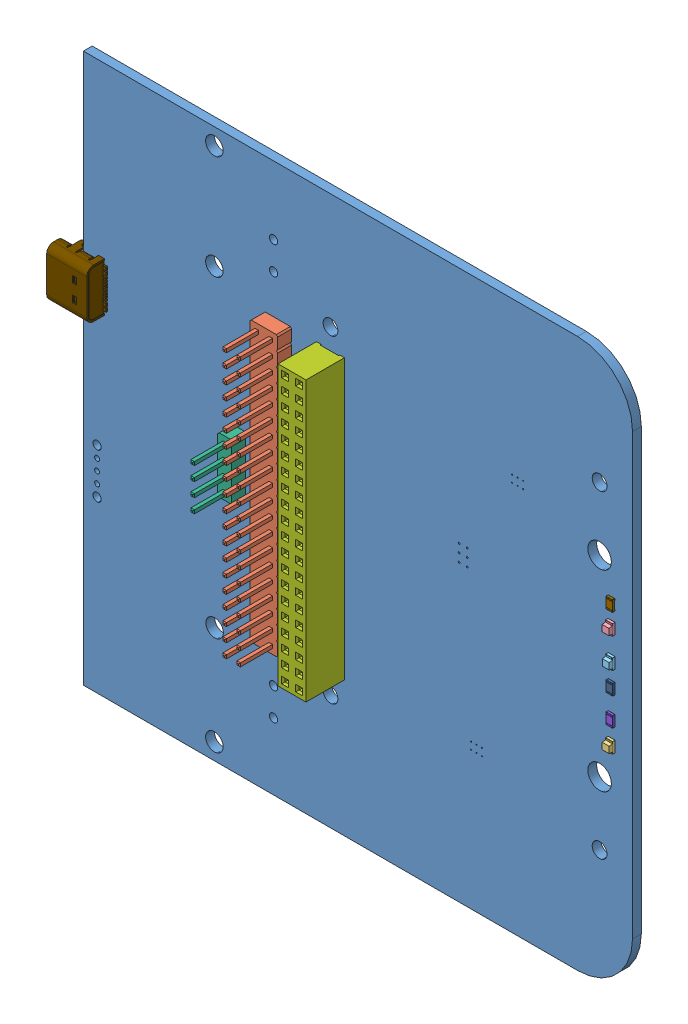
SolidWorks assembly car pcb, configuration 默认. Lengths in mm.
Overall size (103.47 100 12.36).
60 component instances, 54 part files, 4 mates.
Components (placement in the parent):
- car pcb(2)-1: car pcb(2) [默认] at origin size (100 100 12.36)
  - Board_Geoms-1: Board_Geoms [默认] at origin size (100 100 1.6)
    - Pcb-1: Pcb [默认] at (-97.365 149.231 0) size (100 100 1.6)
      - Open CASCADE STEP translator 7.3 1.1.1.1^Pcb-1: Open CASCADE STEP translator 7.3 1.1.1.1^Pcb [默认] at origin size (100 100 1.6) (virtual)
  - Step_Models-1: Step_Models [默认] at origin size (69.83 72.3 12.36)
    - Top-1: Top [默认] at origin size (69.83 50.8 11.64)
      - J6_PinHeader_2x20_P254mm_Vertical_5E973953-1: J6_PinHeader_2x20_P254mm_Vertical_5E973953 [默认] at (34.12 74.135 0) size (5.08 50.8 11.54)
      - D1_LED_0805_2012Metric_5E97381B-1: D1_LED_0805_2012Metric_5E97381B [默认] at (96.209 38.751 0) x (0 1 0) z (0 0 1) size (2 1.25 1.1)
      - D3_LED_0805_2012Metric_5E973846-1: D3_LED_0805_2012Metric_5E973846 [默认] at (96.182 57.3275 0) x (0 1 0) z (0 0 1) size (2 1.25 1.1)
      - D5_LED_0805_2012Metric_5E973871-1: D5_LED_0805_2012Metric_5E973871 [默认] at (96.218 51.946 0) x (0 -1 0) z (0 0 1) size (2 1.25 1.1)
      - J2_PinHeader_1x04_P254mm_Vertical_5E9738C1-1: J2_PinHeader_1x04_P254mm_Vertical_5E9738C1 [默认] at (28.278 53.434 0) size (2.54 10.16 11.54)
      - J5_PinSocket_2x20_P254mm_Vertical_5E975A58-1: J5_PinSocket_2x20_P254mm_Vertical_5E975A58 [默认] at (46.26 74.13 0) size (5.08 50.8 10.1)
      - R4_R_0805_2012Metric_5E99E94D-1: R4_R_0805_2012Metric_5E99E94D [默认] at (96.209 42.815 0) x (0 -1 0) z (0 0 1) size (2 1.2 0.45)
      - R18_R_0805_2012Metric_5E9C048F-1: R18_R_0805_2012Metric_5E9C048F [默认] at (96.182 61.059 0) x (0 -1 0) z (0 0 1) size (2 1.2 0.45)
      - R21_R_0805_2012Metric_5E973B6B-1: R21_R_0805_2012Metric_5E973B6B [默认] at (96.218 47.882 0) x (0 -1 0) z (0 0 1) size (2 1.2 0.45)
    - Bot-1: Bot [默认] at origin size (34.4 72.3 2.22)
      - C5_C_0805_2012Metric_5E97372B-1: C5_C_0805_2012Metric_5E97372B [默认] at (76.411 51.91 -1.6) x (1 0 0) z (0 0 -1) size (2 1.25 1.25)
      - R15_R_0805_2012Metric_5E973B05-1: R15_R_0805_2012Metric_5E973B05 [默认] at (81.491 78.453 -1.6) x (0 1 0) z (0 0 -1) size (2 1.2 0.45)
      - C1_C_1206_3216Metric_5E9736E7-1: C1_C_1206_3216Metric_5E9736E7 [默认] at (50.95 81.1 -1.6) x (0 1 0) z (0 0 -1) size (3.2 1.6 1.6)
      - C2_C_0805_2012Metric_5E9736F8-1: C2_C_0805_2012Metric_5E9736F8 [默认] at (51.5 75.6 -1.6) x (-1 0 0) z (0 0 -1) size (2 1.25 1.25)
      - C3_C_0805_2012Metric_5E973709-1: C3_C_0805_2012Metric_5E973709 [默认] at (76.411 59.403 -1.6) x (-1 0 0) z (0 0 -1) size (2 1.25 1.25)
      - C4_C_1206_3216Metric_5E97BBAC-1: C4_C_1206_3216Metric_5E97BBAC [默认] at (77.046 56.609 -1.6) x (-1 0 0) z (0 0 -1) size (3.2 1.6 1.6)
      - C6_C_0805_2012Metric_5E97B6B1-1: C6_C_0805_2012Metric_5E97B6B1 [默认] at (61.552 53.434 -1.6) x (-1 0 0) z (0 0 -1) size (2 1.25 1.25)
      - C7_C_0805_2012Metric_5E97374D-1: C7_C_0805_2012Metric_5E97374D [默认] at (61.552 56.736 -1.6) x (1 0 0) z (0 0 -1) size (2 1.25 1.25)
      - C8_C_1206_3216Metric_5E97375E-1: C8_C_1206_3216Metric_5E97375E [默认] at (77.046 65.245 -1.6) x (1 0 0) z (0 0 -1) size (3.2 1.6 1.6)
      - C9_C_0805_2012Metric_5E97376F-1: C9_C_0805_2012Metric_5E97376F [默认] at (74.506 69.563 -1.6) x (0 -1 0) z (0 0 -1) size (2 1.25 1.25)
      - C10_C_0805_2012Metric_5E973780-1: C10_C_0805_2012Metric_5E973780 [默认] at (79.078 78.453 -1.6) x (0 1 0) z (0 0 -1) size (2 1.25 1.25)
      - C11_C_1206_3216Metric_5E973791-1: C11_C_1206_3216Metric_5E973791 [默认] at (63.076 69.182 -1.6) x (1 0 0) z (0 0 -1) size (3.2 1.6 1.6)
      - C12_C_1206_3216Metric_5E977737-1: C12_C_1206_3216Metric_5E977737 [默认] at (62.441 23.081 -1.6) x (0 1 0) z (0 0 -1) size (3.2 1.6 1.6)
      - C13_C_1206_3216Metric_5E978263-1: C13_C_1206_3216Metric_5E978263 [默认] at (59.52 23.081 -1.6) x (0 1 0) z (0 0 -1) size (3.2 1.6 1.6)
      - C14_C_1206_3216Metric_5E9737C4-1: C14_C_1206_3216Metric_5E9737C4 [默认] at (79.459 27.018 -1.6) x (-1 0 0) z (0 0 -1) size (3.2 1.6 1.6)
      - C15_C_1206_3216Metric_5E9737D5-1: C15_C_1206_3216Metric_5E9737D5 [默认] at (79.459 23.97 -1.6) x (-1 0 0) z (0 0 -1) size (3.2 1.6 1.6)
      - C16_C_0805_2012Metric_5E9737E6-1: C16_C_0805_2012Metric_5E9737E6 [默认] at (65.997 26.002 -1.6) x (-1 0 0) z (0 0 -1) size (2 1.25 1.25)
      - C17_C_0805_2012Metric_5E9737F7-1: C17_C_0805_2012Metric_5E9737F7 [默认] at (80.059 29.939 -1.6) x (-1 0 0) z (0 0 -1) size (2 1.25 1.25)
      - C18_C_1206_3216Metric_5E973808-1: C18_C_1206_3216Metric_5E973808 [默认] at (73.109 18.036 -1.6) x (0 -1 0) z (0 0 -1) size (3.2 1.6 1.6)
      - D2_D_SMA_5E9BCED4-1: D2_D_SMA_5E9BCED4 [默认] at (70.823 71.468 -1.6) x (0 -1 0) z (0 0 -1) size (5 2.7 2.22)
      - D4_D_SMA_5E9777E8-1: D4_D_SMA_5E9777E8 [默认] at (78.316 33.495 -1.6) x (-1 0 0) z (0 0 -1) size (5 2.7 2.22)
      - Q1_SOT_23_5E99EF72-1: Q1_SOT_23_5E99EF72 [默认] at (59.266 15.207 -1.6) x (-1 0 0) z (0 0 -1) size (2.5 3 1.2)
      - R1_R_0805_2012Metric_5E973A17-1: R1_R_0805_2012Metric_5E973A17 [默认] at (62.695 11.397 -1.6) x (0 1 0) z (0 0 -1) size (2 1.2 0.45)
      - R2_R_0805_2012Metric_5E973A28-1: R2_R_0805_2012Metric_5E973A28 [默认] at (62.695 15.207 -1.6) x (0 1 0) z (0 0 -1) size (2 1.2 0.45)
      - R3_R_0805_2012Metric_5E973A39-1: R3_R_0805_2012Metric_5E973A39 [默认] at (58.504 11.397 -1.6) x (0 -1 0) z (0 0 -1) size (2 1.2 0.45)
      - R5_R_0805_2012Metric_5E973A5B-1: R5_R_0805_2012Metric_5E973A5B [默认] at (50.75 72.5 -1.6) x (0 1 0) z (0 0 -1) size (2 1.2 0.45)
      - R6_R_0805_2012Metric_5E973A6C-1: R6_R_0805_2012Metric_5E973A6C [默认] at (50.7 68.1 -1.6) x (0 1 0) z (0 0 -1) size (2 1.2 0.45)
      - R7_R_0805_2012Metric_5E973A7D-1: R7_R_0805_2012Metric_5E973A7D [默认] at (61.552 59.276 -1.6) x (1 0 0) z (0 0 -1) size (2 1.2 0.45)
      - R8_R_0805_2012Metric_5E973A8E-1: R8_R_0805_2012Metric_5E973A8E [默认] at (72.728 48.608 -1.6) x (0 1 0) z (0 0 -1) size (2 1.2 0.45)
      - R9_R_0805_2012Metric_5E97BAD9-1: R9_R_0805_2012Metric_5E97BAD9 [默认] at (76.411 49.37 -1.6) x (-1 0 0) z (0 0 -1) size (2 1.2 0.45)
      - R10_R_0805_2012Metric_5E973AB0-1: R10_R_0805_2012Metric_5E973AB0 [默认] at (70.188 61.054 -1.6) x (0 -1 0) z (0 0 -1) size (2 1.2 0.45)
      - R11_R_0805_2012Metric_5E973AC1-1: R11_R_0805_2012Metric_5E973AC1 [默认] at (72.728 61.054 -1.6) x (0 1 0) z (0 0 -1) size (2 1.2 0.45)
      - R12_R_0805_2012Metric_5E97B756-1: R12_R_0805_2012Metric_5E97B756 [默认] at (66.378 61.054 -1.6) x (0 1 0) z (0 0 -1) size (2 1.2 0.45)
      - R13_R_0805_2012Metric_5E973AE3-1: R13_R_0805_2012Metric_5E973AE3 [默认] at (76.665 78.453 -1.6) x (0 1 0) z (0 0 -1) size (2 1.2 0.45)
      - R14_R_0805_2012Metric_5E973AF4-1: R14_R_0805_2012Metric_5E973AF4 [默认] at (81.745 65.245 -1.6) x (1 0 0) z (0 0 -1) size (2 1.2 0.45)
      - R16_R_0805_2012Metric_5E973B16-1: R16_R_0805_2012Metric_5E973B16 [默认] at (83.904 73.627 -1.6) x (0 1 0) z (0 0 -1) size (2 1.2 0.45)
      - R17_R_0805_2012Metric_5E973B27-1: R17_R_0805_2012Metric_5E973B27 [默认] at (83.904 78.453 -1.6) x (0 -1 0) z (0 0 -1) size (2 1.2 0.45)
      - R19_R_0805_2012Metric_5E973B49-1: R19_R_0805_2012Metric_5E973B49 [默认] at (62.568 27.78 -1.6) x (0 -1 0) z (0 0 -1) size (2 1.2 0.45)
      - R20_R_0805_2012Metric_5E973B5A-1: R20_R_0805_2012Metric_5E973B5A [默认] at (65.997 28.542 -1.6) x (1 0 0) z (0 0 -1) size (2 1.2 0.45)
      - R22_R_0805_2012Metric_5E973B7C-1: R22_R_0805_2012Metric_5E973B7C [默认] at (70.4133 18.636 -1.6) x (0 -1 0) z (0 0 -1) size (2 1.2 0.45)
      - R23_R_0805_2012Metric_5E9785CC-1: R23_R_0805_2012Metric_5E9785CC [默认] at (65.362 18.636 -1.6) x (0 -1 0) z (0 0 -1) size (2 1.2 0.45)
      - R24_R_0805_2012Metric_5E973B9E-1: R24_R_0805_2012Metric_5E973B9E [默认] at (67.8877 18.636 -1.6) x (0 -1 0) z (0 0 -1) size (2 1.2 0.45)
      - U1_TSSOP_16_1EP_44x5mm_Pitch065mm_EP34x5mm_5E973BE1-1: U1_TSSOP_16_1EP_44x5mm_Pitch065mm_EP34x5mm_5E973BE1 [默认] at (69.172 55.085 -1.6) x (1 0 0) z (0 0 -1) size (5.3 5.3 1.6)
- User Library-USB Type C Port (SMD Type)-1: User Library-USB Type C Port (SMD Type) [Default] at (3.827 64.702 1.605) x (0 -1 0) z (0 0 -1) size (8.94 7.9 4.2)
Mates (geometry in assembly coordinates):
- 重合4: coincident: plane of assembly; plane of assembly; plane of car pcb(2)-1/Board_Geoms-1/Pcb-1/Open CASCADE STEP translator 7.3 1.1.1.1^Pcb-1 through (48.8122 50 0) normal (0 0 1); plane of User Library-USB Type C Port (SMD Type)-1 through (-3.473 69.172 0) normal (0 0 -1)
- 平行1: parallel: plane of assembly; plane of assembly; plane of car pcb(2)-1/Board_Geoms-1/Pcb-1/Open CASCADE STEP translator 7.3 1.1.1.1^Pcb-1 through (0 0 0) normal (-1 0 0); plane of User Library-USB Type C Port (SMD Type)-1 through (3.827 61.482 1.96) normal (1 0 0)
- 重合6: coincident: plane of assembly; plane of assembly; plane of car pcb(2)-1/Board_Geoms-1/Pcb-1/Open CASCADE STEP translator 7.3 1.1.1.1^Pcb-1 through (3.602 69.172 0) normal (0 -1 0); plane of User Library-USB Type C Port (SMD Type)-1 through (-3.473 69.172 0) normal (0 1 0)
- 重合8: coincident: point of assembly; plane of assembly; moEndPointRef_w of car pcb(2)-1/Board_Geoms-1/Pcb-1/Open CASCADE STEP translator 7.3 1.1.1.1^Pcb-1; plane of User Library-USB Type C Port (SMD Type)-1 through (3.827 64.702 1.605) normal (1 0 0)
